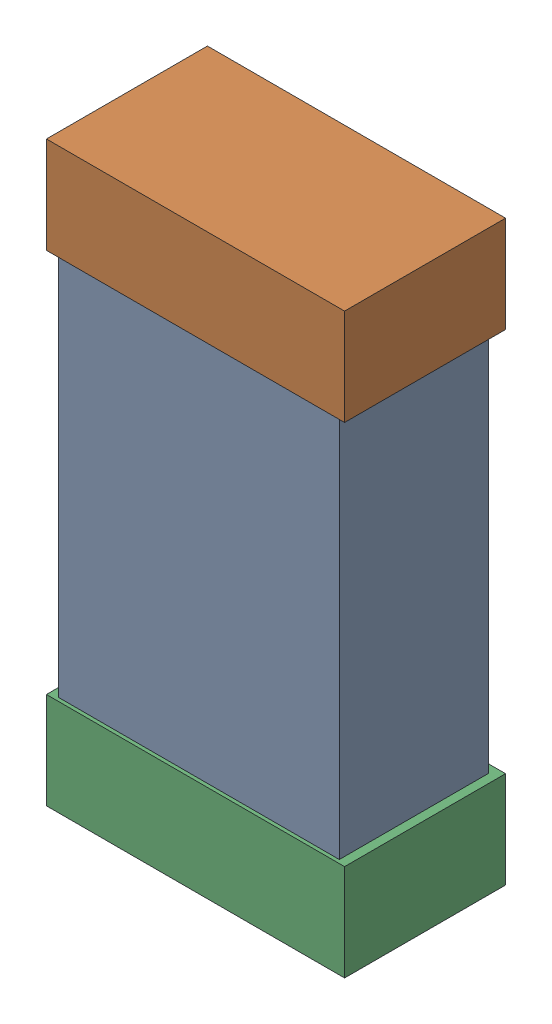
SolidWorks assembly R12, configuration Default. Lengths in mm.
Overall size (0.85 1.65 0.46).
6 component instances, 2 part files, 0 mates.
Components (placement in the parent):
- 432124816_49-1: 432124816_49 [Default] at (34.1459 22.0611 0.025) size (0.8 1.5 0.42)
  - Extruded (1)-1: Extruded (1) [Default] at origin size (0.8 1.5 0.42)
- 432138512_98-1: 432138512_98 [Default] at (34.1459 22.747 0.001) size (0.85 0.28 0.46)
  - Extruded-1: Extruded [Default] at origin size (0.85 0.28 0.46)
- 432138512_99-1: 432138512_99 [Default] at (34.1459 21.3754 0.001) size (0.85 0.28 0.46)
  - Extruded-1: Extruded [Default] at origin size (0.85 0.28 0.46)
